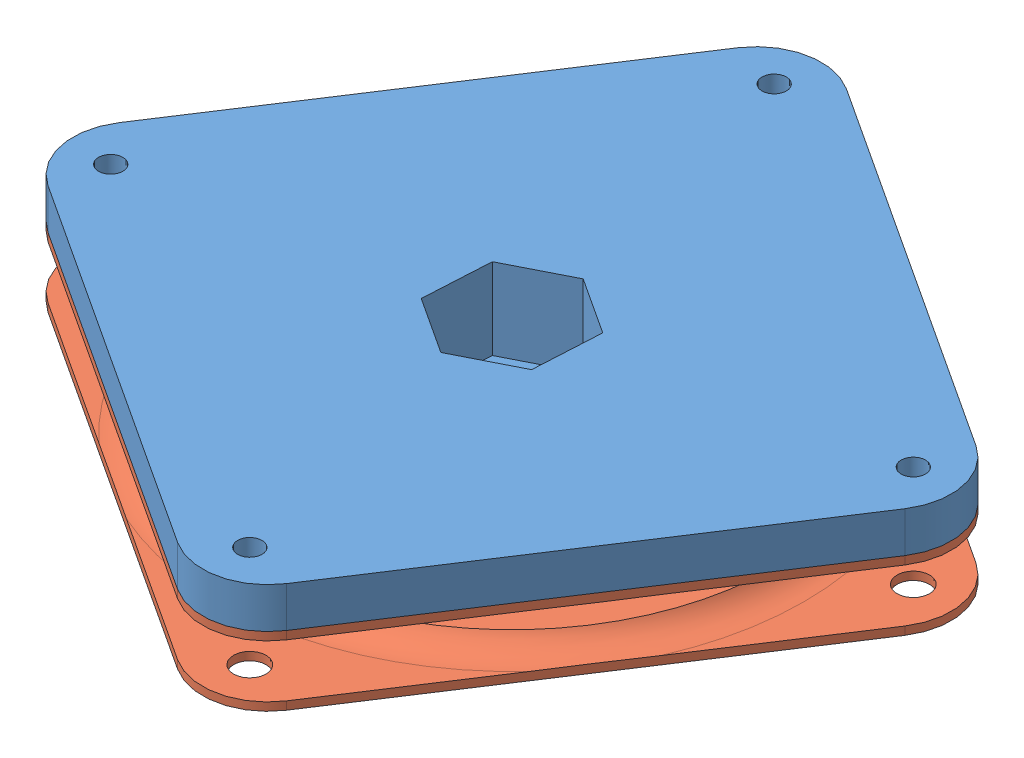
SolidWorks assembly HorRotate_assembly, configuration Default. Lengths in mm.
Overall size (98.27 28 98.27).
5 component instances, 4 part files, 11 mates.
Components (placement in the parent):
- HorRotateAdapter2DimTop-1: HorRotateAdapter2DimTop [Default] at (20.0952 -63.1658 18.2203) x (0.998542 0 -0.053975) z (0.053975 0 0.998542) (suppressed, hidden)
- HorRotateAdapter-2: HorRotateAdapter [Default] at (63.9303 -63.1658 29.992) x (-0.837169 0 -0.546944) z (-0.546944 0 0.837169) size (71 28 71)
- Tripod_head bolt-1: Tripod_head bolt [Default] at (53.6273 -73.1658 -19.144) x (-0.998542 0 0.053975) z (-0.053975 0 -0.998542) (suppressed, hidden)
- LazySusan_part-1: LazySusan_part [Default] at (63.9303 -71.1658 29.992) x (0.546944 0 -0.837169) z (0.837169 0 0.546944) size (71 3 71)
- LazySusan_part-2: LazySusan_part [Default] at (63.9303 -73.6658 29.992) x (-0.837169 0 -0.546944) z (-0.546944 0 0.837169) size (71 3 71)
Mates (geometry in assembly coordinates):
- Coincident9: coincident anti-aligned: plane of HorRotateAdapter2DimTop-1 through (5.1016 -63.1658 -6.2696) normal (0 -1 0); plane of HorRotateAdapter-2 through (5.1016 -63.1658 -6.2696) normal (0 1 0)
- Coincident10: coincident anti-aligned: plane of HorRotateAdapter-2; plane of Tripod_head bolt-1 through (45.5444 -66.1658 -19.1639) normal (-0.867254 0 0.497866)
- Coincident11: coincident anti-aligned: plane of HorRotateAdapter-2 through (5.1016 -73.1658 -6.2696) normal (0 1 0); plane of Tripod_head bolt-1 through (53.6273 -73.1658 -19.144) normal (0 -1 0)
- Concentric1: concentric aligned: cylinder of HorRotateAdapter-2 through (53.6273 -70.1658 -19.144) axis (0 -1 0) radius 3; cylinder of Tripod_head bolt-1 through (53.6273 -46.1658 -19.144) axis (0 -1 0) radius 4.75
- Coincident12: coincident aligned: plane of HorRotateAdapter2DimTop-1 through (40.7528 -58.1658 -67.6698) normal (0.502131 0 -0.864792); plane of HorRotateAdapter-2
- Coincident13: coincident aligned: plane of HorRotateAdapter2DimTop-1 through (5.1016 -58.1658 -6.2696) normal (-0.864792 0 -0.502131); plane of HorRotateAdapter-2
- Distance1: distance = 2.5 mm anti-aligned: plane of LazySusan_part-2 through (63.9303 -73.6658 29.992) normal (0 1 0); plane of LazySusan_part-1 through (6.933 -71.1658 -0.7012) normal (0 -1 0)
- Concentric2: concentric aligned: circle of LazySusan_part-1; circle of LazySusan_part-2
- Coincident15: coincident aligned: plane of HorRotateAdapter-2 through (72.0701 -68.1658 27.5503) normal (0.917425 0 0.397908); plane of LazySusan_part-1 through (72.0701 -68.1658 27.5503) normal (0.917425 0 0.397908)
- Coincident16: coincident aligned: plane of HorRotateAdapter-2 through (35.1845 -68.1658 -65.8384) normal (0.397908 0 -0.917425); plane of LazySusan_part-1 through (35.1845 -68.1658 -65.8384) normal (0.397908 0 -0.917425)
- Coincident17: coincident anti-aligned: plane of HorRotateAdapter-2 through (6.933 -68.1658 -0.7012) normal (0 -1 0); plane of LazySusan_part-1 through (6.933 -68.1658 -0.7012) normal (0 1 0)
